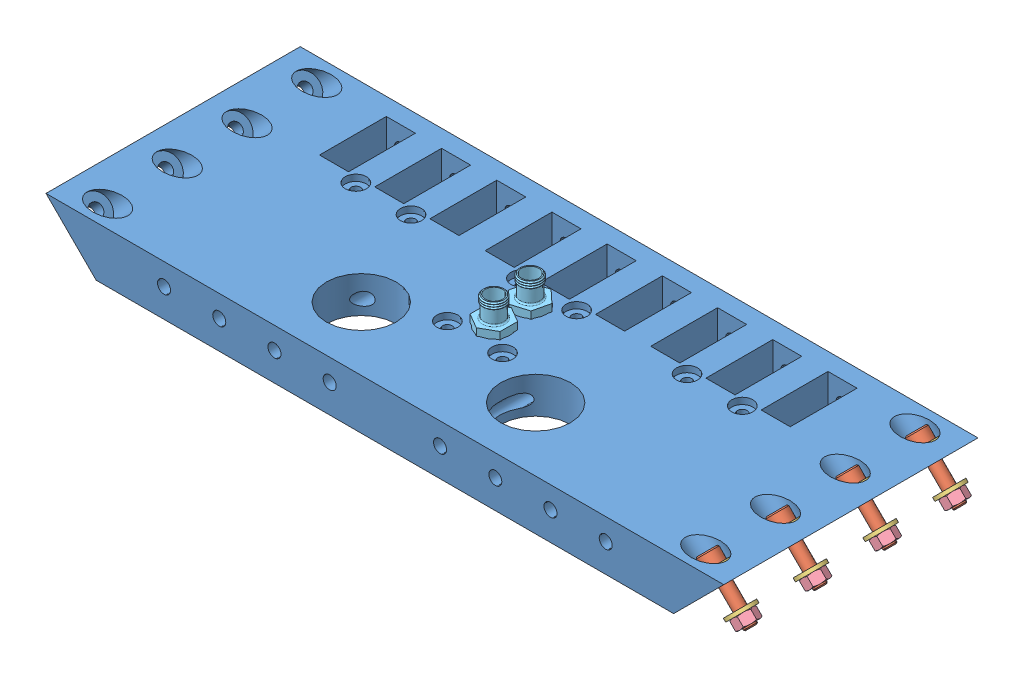
SolidWorks assembly joint_plate_assy_vert_sd_1108, configuration Default. Lengths in mm.
Overall size (476.94 56.8 175).
20 component instances, 5 part files, 7 mates.
Components (placement in the parent):
- joint_plate_vert_sd_1108-1: joint_plate_vert_sd_1108 [Default] at origin size (466.51 34.5 175)
- joint_plate_bolts_assy1x48-1: joint_plate_bolts_assy1x48 [Default] at (-0.2085 -212.2842 16) x (0.707107 -0.707107 0) z (0 0 1) size (43 18.8 162.8)
  - Socket Head Cap Screw_AM-1: Socket Head Cap Screw_AM [B18.3.1M - 8 x 1.25 x 35 Hex SHCS -- 35NHX] at (-21 313.5152 0) size (43 13 13)
  - flat washer narrow_am-1: flat washer narrow_am [B18.22M - Plain washer, 8 mm, narrow] at (-10.7 313.5152 0) size (2.3 18.8 18.8)
  - flat washer narrow_am-2: flat washer narrow_am [B18.22M - Plain washer, 8 mm, narrow] at (13.615 313.5152 0) size (2.3 18.8 18.8)
  - Hex Nut Style 1_AM-1: Hex Nut Style 1_AM [B18.2.4.1M - Hex nut, Style 1,  M8 x 1.25 --D-N] at (20.415 313.5152 0) x (0 0 -1) z (1 0 0) size (13 15.01 6.8)
  - Hex Nut Style 1_AM-2: Hex Nut Style 1_AM [B18.2.4.1M - Hex nut, Style 1,  M8 x 1.25 --D-N] at (20.415 313.5152 48) x (0 0 -1) z (1 0 0) size (13 15.01 6.8)
  - Hex Nut Style 1_AM-3: Hex Nut Style 1_AM [B18.2.4.1M - Hex nut, Style 1,  M8 x 1.25 --D-N] at (20.415 313.5152 96) x (0 0 -1) z (1 0 0) size (13 15.01 6.8)
  - Hex Nut Style 1_AM-4: Hex Nut Style 1_AM [B18.2.4.1M - Hex nut, Style 1,  M8 x 1.25 --D-N] at (20.415 313.5152 144) x (0 0 -1) z (1 0 0) size (13 15.01 6.8)
  - flat washer narrow_am-3: flat washer narrow_am [B18.22M - Plain washer, 8 mm, narrow] at (13.615 313.5152 48) size (2.3 18.8 18.8)
  - flat washer narrow_am-4: flat washer narrow_am [B18.22M - Plain washer, 8 mm, narrow] at (13.615 313.5152 96) size (2.3 18.8 18.8)
  - flat washer narrow_am-5: flat washer narrow_am [B18.22M - Plain washer, 8 mm, narrow] at (13.615 313.5152 144) size (2.3 18.8 18.8)
  - flat washer narrow_am-6: flat washer narrow_am [B18.22M - Plain washer, 8 mm, narrow] at (-10.7 313.5152 48) size (2.3 18.8 18.8)
  - flat washer narrow_am-7: flat washer narrow_am [B18.22M - Plain washer, 8 mm, narrow] at (-10.7 313.5152 96) size (2.3 18.8 18.8)
  - flat washer narrow_am-8: flat washer narrow_am [B18.22M - Plain washer, 8 mm, narrow] at (-10.7 313.5152 144) size (2.3 18.8 18.8)
  - Socket Head Cap Screw_AM-2: Socket Head Cap Screw_AM [B18.3.1M - 8 x 1.25 x 35 Hex SHCS -- 35NHX] at (-21 313.5152 48) size (43 13 13)
  - Socket Head Cap Screw_AM-3: Socket Head Cap Screw_AM [B18.3.1M - 8 x 1.25 x 35 Hex SHCS -- 35NHX] at (-21 313.5152 96) size (43 13 13)
  - Socket Head Cap Screw_AM-4: Socket Head Cap Screw_AM [B18.3.1M - 8 x 1.25 x 35 Hex SHCS -- 35NHX] at (-21 313.5152 144) size (43 13 13)
- water_adapter_b_1106-1: water_adapter_b_1106 [Default] at (0 0 75) x (0.95672 0 -0.291009) z (0 1 0) size (24 24 44)
- water_adapter_b_1106-2: water_adapter_b_1106 [Default] at (0 0 100) x (0.869223 0 -0.49442) z (0 1 0) size (24 24 44)
Mates (geometry in assembly coordinates):
- Concentric1: concentric anti-aligned: cylinder of joint_plate_vert_sd_1108-1 through (0 25 75) axis (0 1 0) radius 11; cylinder of water_adapter_b_1106-1 through (0 30 75) axis (0 -1 0) radius 12
- Concentric2: concentric anti-aligned: cylinder of joint_plate_vert_sd_1108-1 through (0 25 100) axis (0 1 0) radius 11; cylinder of water_adapter_b_1106-2 through (0 30 100) axis (0 -1 0) radius 12
- Coincident1: coincident anti-aligned: plane of joint_plate_vert_sd_1108-1 through (213.9142 16.9706 160) normal (-0.707107 0.707107 0); plane of joint_plate_bolts_assy1x48-1/flat washer narrow_am-8 through (217.1386 20.195 160) normal (0.707107 -0.707107 0)
- Concentric3: concentric anti-aligned: cylinder of joint_plate_vert_sd_1108-1 through (-13.6863 244.5711 160) axis (0.707107 -0.707107 0) radius 4.5; cylinder of joint_plate_bolts_assy1x48-1/Socket Head Cap Screw_AM-4 through (184.1804 46.7044 160) axis (-0.707107 0.707107 0) radius 4
- Concentric4: concentric anti-aligned: cylinder of joint_plate_vert_sd_1108-1 through (-13.6863 244.5711 16) axis (0.707107 -0.707107 0) radius 4.5; cylinder of joint_plate_bolts_assy1x48-1/Socket Head Cap Screw_AM-1 through (184.1804 46.7044 16) axis (-0.707107 0.707107 0) radius 4
- Coincident2: coincident aligned: plane of joint_plate_vert_sd_1108-1 through (-208.2574 0 175) normal (0 -1 0); plane of water_adapter_b_1106-1 through (0 0 75) normal (0 -1 0)
- Coincident3: coincident aligned: plane of joint_plate_vert_sd_1108-1 through (-208.2574 0 175) normal (0 -1 0); plane of water_adapter_b_1106-2 through (0 0 100) normal (0 -1 0)
